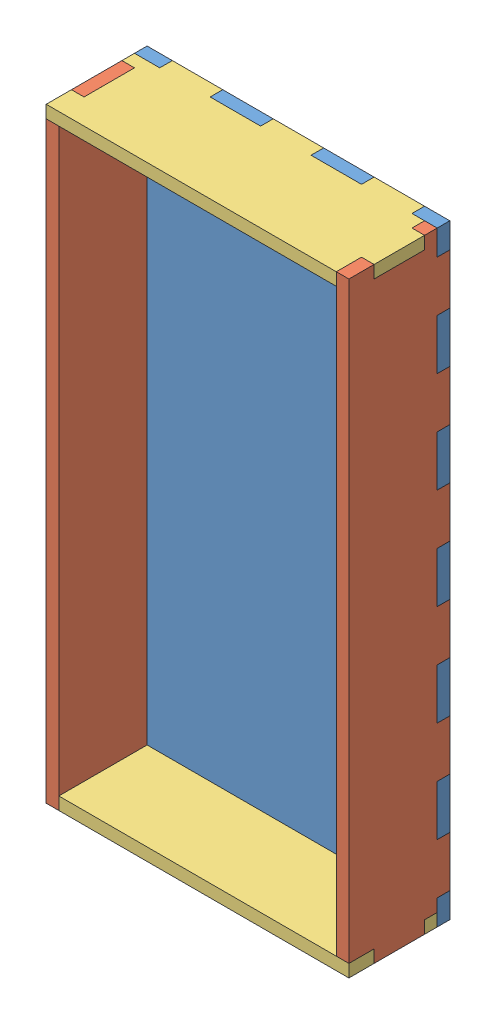
SolidWorks assembly 6x3x1 box, configuration Default. Lengths in mm.
Overall size (76.2 152.4 25.4).
5 component instances, 3 part files, 12 mates.
Components (placement in the parent):
- 6x3 bottom-1: 6x3 bottom [Default] at (-53.6917 -75.602 6.2338) size (76.2 152.4 3.17)
- 6x1 side-1: 6x1 side [Default] at (-53.6917 -75.602 31.6338) x (0 0 -1) z (1 0 0) size (25.4 152.4 3.17)
- 3x1 side-1: 3x1 side [Default] at (-53.6917 76.798 31.6338) x (0 0 -1) z (0 -1 0) size (25.4 76.2 3.17)
- 6x1 side-2: 6x1 side [Default] at (22.5083 76.798 31.6338) x (0 0 -1) z (-1 0 0) size (25.4 152.4 3.17)
- 3x1 side-2: 3x1 side [Default] at (22.5083 -75.602 31.6338) x (0 0 -1) z (0 1 0) size (25.4 76.2 3.17)
Mates (geometry in assembly coordinates):
- Coincident4: coincident aligned: plane of 6x3 bottom-1 through (-53.6917 76.798 6.2338) normal (0 0 -1); plane of 6x1 side-1 through (-50.5167 -75.602 6.2338) normal (0 0 -1)
- Coincident5: coincident aligned: plane of 6x3 bottom-1 through (-53.6917 -75.602 9.4088) normal (-1 0 0); plane of 6x1 side-1 through (-53.6917 76.798 31.6338) normal (-1 0 0)
- Coincident6: coincident aligned: plane of 6x3 bottom-1 through (-53.6917 76.798 9.4088) normal (0 1 0); plane of 6x1 side-1 through (-50.5167 76.798 31.6338) normal (0 1 0)
- Coincident8: coincident aligned: plane of 6x3 bottom-1 through (-53.6917 76.798 6.2338) normal (0 0 -1); plane of 3x1 side-1 through (-53.6917 73.623 6.2338) normal (0 0 -1)
- Coincident9: coincident aligned: plane of 6x3 bottom-1 through (-53.6917 76.798 9.4088) normal (0 1 0); plane of 3x1 side-1 through (22.5083 76.798 31.6338) normal (0 1 0)
- Coincident10: coincident aligned: plane of 6x1 side-1 through (-53.6917 76.798 31.6338) normal (-1 0 0); plane of 3x1 side-1 through (-53.6917 73.623 31.6338) normal (-1 0 0)
- Coincident11: coincident aligned: plane of 6x3 bottom-1 through (-53.6917 76.798 6.2338) normal (0 0 -1); plane of 6x1 side-2 through (19.3333 76.798 6.2338) normal (0 0 -1)
- Coincident13: coincident aligned: plane of 6x3 bottom-1 through (22.5083 -75.602 9.4088) normal (1 0 0); plane of 6x1 side-2
- Coincident14: coincident aligned: plane of 3x1 side-1 through (22.5083 76.798 31.6338) normal (0 1 0); plane of 6x1 side-2 through (19.3333 76.798 31.6338) normal (0 1 0)
- Coincident15: coincident aligned: plane of 6x3 bottom-1 through (-53.6917 -75.602 9.4088) normal (0 -1 0); plane of 3x1 side-2
- Coincident16: coincident aligned: plane of 6x1 side-1 through (-53.6917 76.798 31.6338) normal (-1 0 0); plane of 3x1 side-2 through (-53.6917 -72.427 31.6338) normal (-1 0 0)
- Coincident17: coincident aligned: plane of 6x3 bottom-1 through (-53.6917 76.798 6.2338) normal (0 0 -1); plane of 3x1 side-2 through (22.5083 -72.427 6.2338) normal (0 0 -1)
